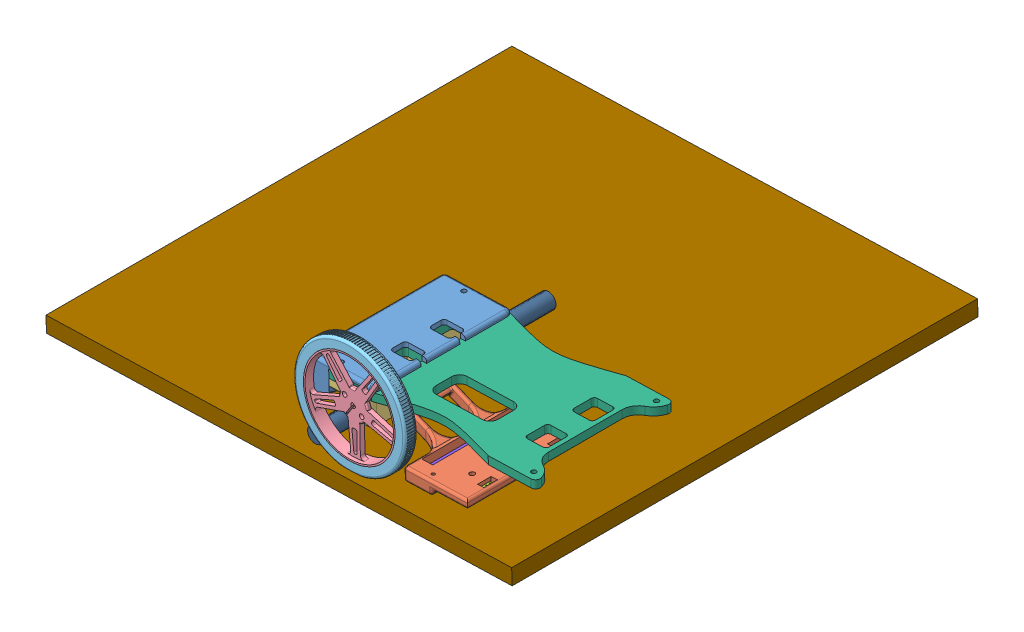
SolidWorks assembly Montagem correta, configuration Valor predeterminado. Lengths in mm.
Overall size (304.4 100.09 300).
12 component instances, 10 part files, 24 mates.
Components (placement in the parent):
- SuporteDoArraynovo-1: SuporteDoArraynovo [Valor predeterminado] at (-52.5025 4.4822 8.1423) x (0.030172 -0.999545 0) z (0 0 -1) size (33 43.95 89)
- Peça5-2: Peça5 [Valor predeterminado] at (-57.0225 -17.7609 4.1816) x (0.999545 0.030172 0) z (0 0 1) size (82.5 24.77 78.95)
- suporte motor-1: suporte motor [Valor predeterminado] at (41.069 2.3044 0.1078) x (0 0 1) z (0.030172 -0.999545 0) size (89 30.54 15)
- Roda-70mm-1: Roda-70mm [Valor predeterminado] at (-43.2406 -5.2428 34.0439) x (0.843209 -0.537587 0) z (0 0 1) size (71.92 71.92 8.56)
  - pololu wheel 70x8mm ref.14251-1: pololu wheel 70x8mm ref.14251 [Valor predeterminado] at origin size (65 65 8.56)
  - pololu wheel 70x8mm ref.14252-1: pololu wheel 70x8mm ref.14252 [Valor predeterminado] at origin size (71.92 71.92 8)
- chassi-1: chassi [Valor predeterminado] at (40.9181 7.3021 0.1078) x (0 0 1) z (0.030172 -0.999545 0) size (89 136.28 5)
- QRE-1: QRE [Predeterminado] at (6.0013 -32.4635 -34.2034) x (0.999545 0.030172 0) z (0.030172 -0.999545 0) size (12.8 7.17 2.73)
- QRE-2: QRE [Predeterminado] at (6.0013 -32.4635 10.7966) x (0.999545 0.030172 0) z (0.030172 -0.999545 0) size (12.8 7.17 2.73)
- Array-2: Array [Valor predeterminado] at (-9.6554 -37.6153 -15.014) x (0 0 -1) z (0.999545 0.030172 0) size (74.93 3.17 12.7)
- chao-2: chao [Valor predeterminado] at (-219.7887 -55.2882 -33.7649) x (0 0 -1) z (-0.030172 0.999545 0) size (300 300 10)
- Lapis-1: Lapis [Valor predeterminado] at (-65.3107 -37.308 -112.4561) x (0.999981 0.006097 0) z (0 0 1) size (10 10 150)
Mates (geometry in assembly coordinates):
- Concêntrico3: concentric anti-aligned: circle of SuporteDoArraynovo-1; circle of chassi-1
- Coincidente2: coincident anti-aligned: circle of SuporteDoArraynovo-1; circle of chassi-1
- Concêntrico4: concentric anti-aligned: circle of SuporteDoArraynovo-1; circle of suporte motor-1
- Concêntrico5: concentric anti-aligned: circle of SuporteDoArraynovo-1; circle of suporte motor-1
- Coincidente5: coincident anti-aligned: plane of suporte motor-1 through (-37.2942 -0.061 -49.4561) normal (-0.030172 0.999545 0); plane of chassi-1 through (3.2873 1.1639 27.7637) normal (0.030172 -0.999545 0)
- Coincidente6: coincident anti-aligned: plane of suporte motor-1 through (-61.3699 -15.7946 36.5439) normal (0 0 1); plane of Roda-70mm-1/pololu wheel 70x8mm ref.14251-1 through (-33.2764 -42.2618 36.5439) normal (0 0 -1)
- Concêntrico6: concentric anti-aligned: circle of suporte motor-1; circle of Roda-70mm-1/pololu wheel 70x8mm ref.14251-1
- Coincidente12: coincident anti-aligned: plane of SuporteDoArraynovo-1 through (-61.9226 -12.8099 4.1816) normal (0 0 1); plane of Peça5-2 through (-57.0225 -17.7609 4.1816) normal (0 0 -1)
- Coincidente13: coincident anti-aligned: plane of Peça5-2 through (-56.5217 -34.3508 4.1816) normal (0.030172 -0.999545 0); plane of QRE-1 through (6.0013 -32.4635 -34.2034) normal (-0.030172 0.999545 0)
- Concêntrico12: concentric aligned: circle of Peça5-2; circle of QRE-1
- Paralelo2: parallel anti-aligned: plane of Peça5-2 through (20.1948 -32.0351 -26.2684) normal (-0.999545 -0.030172 0); plane of QRE-1 through (18.8299 -33.2168 -34.2034) normal (0.999545 0.030172 0)
- Concêntrico13: concentric aligned: circle of Peça5-2; circle of QRE-2
- Coincidente15: coincident anti-aligned: plane of Peça5-2 through (-56.5217 -34.3508 4.1816) normal (0.030172 -0.999545 0); plane of QRE-2 through (6.0013 -32.4635 10.7966) normal (-0.030172 0.999545 0)
- Paralelo3: parallel anti-aligned: plane of Peça5-2 through (20.1948 -32.0351 18.7316) normal (-0.999545 -0.030172 0); plane of QRE-2 through (18.8299 -33.2168 10.7966) normal (0.999545 0.030172 0)
- Concêntrico14: concentric aligned: circle of SuporteDoArraynovo-1; circle of Peça5-2
- Coincidente18: coincident anti-aligned: plane of Peça5-2 through (-56.4764 -35.8521 4.1816) normal (0.030172 -0.999545 0); plane of Array-2 through (-9.7512 -34.4417 -15.014) normal (-0.030172 0.999545 0)
- Coincidente19: coincident anti-aligned: plane of Peça5-2 through (-16.743 -34.6528 29.8816) normal (0 0 -1); plane of Array-2 through (-15.4436 -34.6136 29.8816) normal (0 0 1)
- Coincidente20: coincident anti-aligned: plane of Peça5-2 through (-2.7494 -34.2304 29.8816) normal (-0.999545 -0.030172 0); plane of Array-2 through (-2.7494 -34.2304 29.8816) normal (0.999545 0.030172 0)
- Distância5: distance = 100 mm anti-aligned: plane of SuporteDoArraynovo-1 through (-61.07 -25.7901 -52.4561) normal (0 0 -1); plane of chao-2 through (-233.0069 -45.6826 47.5439) normal (0 0 1)
- Distância4: distance = 100 mm aligned: plane of suporte motor-1 through (-33.843 -14.9637 33.5439) normal (0.999545 0.030172 0); plane of chao-2 through (66.8565 -36.6311 47.5439) normal (0.999545 0.030172 0)
- Coincidente24: coincident: point of Roda-70mm-1/pololu wheel 70x8mm ref.14252-1; plane of chao-2 through (-220.0905 -45.2927 -33.7649) normal (-0.030172 0.999545 0)
- Distância6: distance = 10 mm aligned: plane of Lapis-1 through (-69.5772 -35.7472 37.5439) normal (0 0 1); plane of chao-2 through (-233.0069 -45.6826 47.5439) normal (0 0 1)
- Tangente2: tangent anti-aligned: plane of chao-2 through (-220.0905 -45.2927 -33.7649) normal (-0.030172 0.999545 0); cylinder of Lapis-1 through (-69.5772 -35.7472 37.5439) axis (0 0 -1) radius 5
- Coincidente27: coincident: line of Peça5-2 through (-2.6136 -38.7281 29.8816) axis (-0.999545 -0.030172 0); plane of chao-2 through (-220.0905 -45.2927 -33.7649) normal (-0.030172 0.999545 0)
